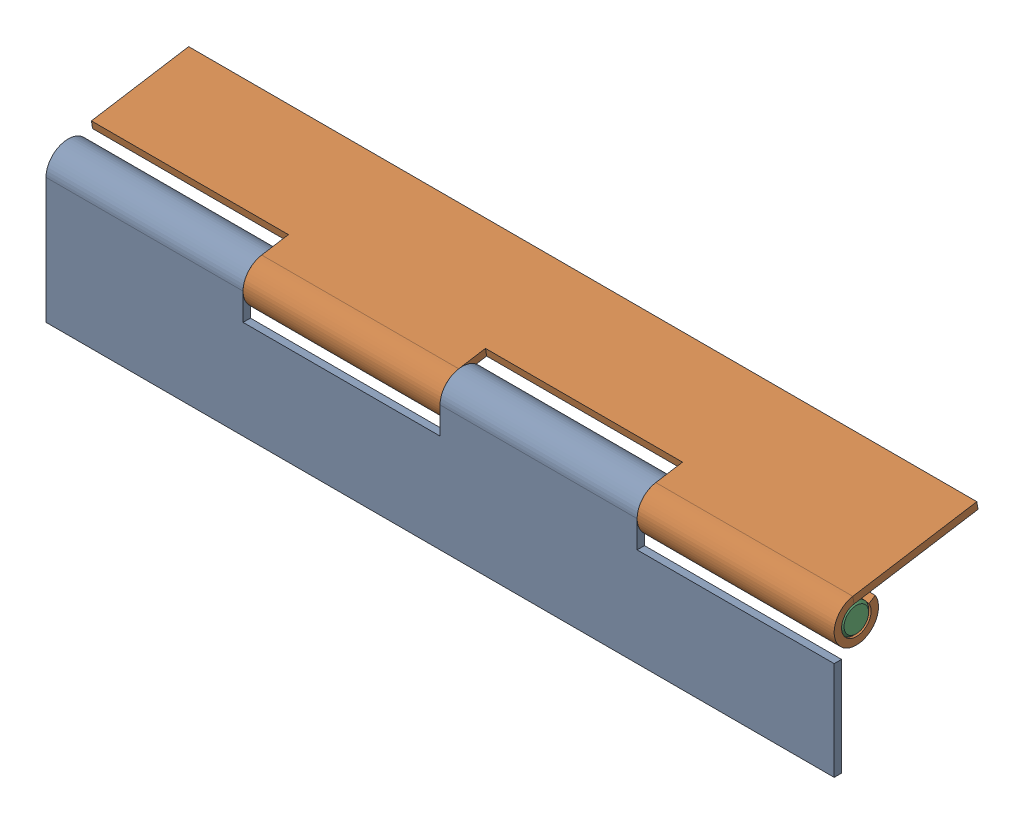
SolidWorks assembly MirrorBASE-Cabinet Hinge1, configuration Default. Lengths in mm.
Overall size (160 34 31.05).
3 component instances, 2 part files, 4 mates.
Components (placement in the parent):
- MirrorBASE-Cabinet Hinge Flange-1: MirrorBASE-Cabinet Hinge Flange [Default] at (-155.1002 71.3389 -114.9534) size (160 30 9)
- MirrorBASE-Cabinet Hinge Flange-2: MirrorBASE-Cabinet Hinge Flange [Default] at (4.8998 103.8583 -142.6511) x (-1 0 0) z (0 0.987259 0.159123) size (160 30 9)
- MirrorBASE-Cabinet Hinge Pin-1: MirrorBASE-Cabinet Hinge Pin [Default] at (-155.1002 93.2182 -117.9534) x (0 0 1) z (-1 0 0) size (6 6 160)
Mates (geometry in assembly coordinates):
- Concentric1: concentric: cylinder of assembly; cylinder of assembly; cylinder of MirrorBASE-Cabinet Hinge Flange-2 through (4.8998 96.8389 -117.9534) axis (1 0 0) radius 3; cylinder of MirrorBASE-Cabinet Hinge Pin-1 through (4.8998 96.8389 -117.9534) axis (-1 0 0) radius 3
- Coincident1: coincident: plane of assembly; plane of assembly; plane of MirrorBASE-Cabinet Hinge Flange-2 through (4.8998 96.8389 -117.9534) normal (1 0 0); plane of MirrorBASE-Cabinet Hinge Pin-1 through (4.8998 96.8389 -117.9534) normal (1 0 0)
- Concentric2: concentric: cylinder of assembly; cylinder of assembly; cylinder of MirrorBASE-Cabinet Hinge Flange-1 through (-75.1002 96.8389 -117.9534) axis (-1 0 0) radius 3; cylinder of MirrorBASE-Cabinet Hinge Pin-1 through (4.8998 96.8389 -117.9534) axis (-1 0 0) radius 3
- Coincident2: coincident: plane of assembly; plane of assembly; plane of MirrorBASE-Cabinet Hinge Flange-1 through (-35.1002 96.8389 -117.9534) normal (1 0 0); plane of MirrorBASE-Cabinet Hinge Flange-2 through (-35.1002 96.8389 -117.9534) normal (-1 0 0)
